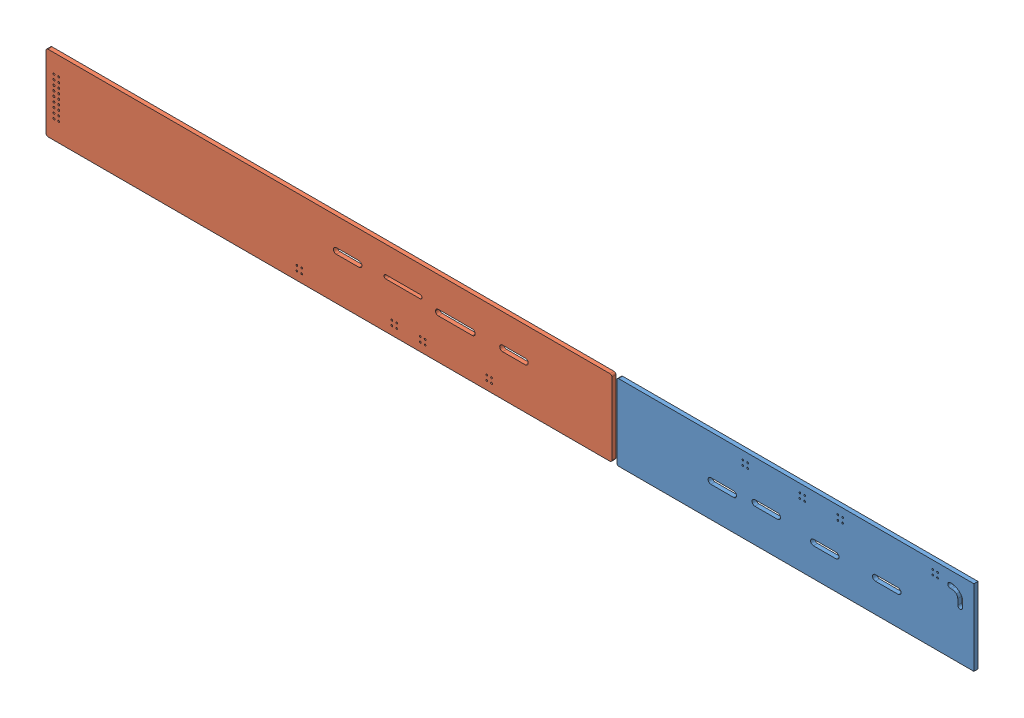
SolidWorks assembly board, configuration Default. Lengths in mm.
Overall size (488.85 40 2.16).
3 component instances, 2 part files, 0 mates.
Components (placement in the parent):
- Board-1-1: Board-1 [По умолчанию] at origin size (488.85 40 2.16)
  - Board-Part-1-1: Board-Part-1 [По умолчанию] at (0 0 -2.1614) size (188.1 40 2.16)
  - Board-Part-2-1: Board-Part-2 [По умолчанию] at (0 0 -2.1614) size (298.1 40 2.16)
